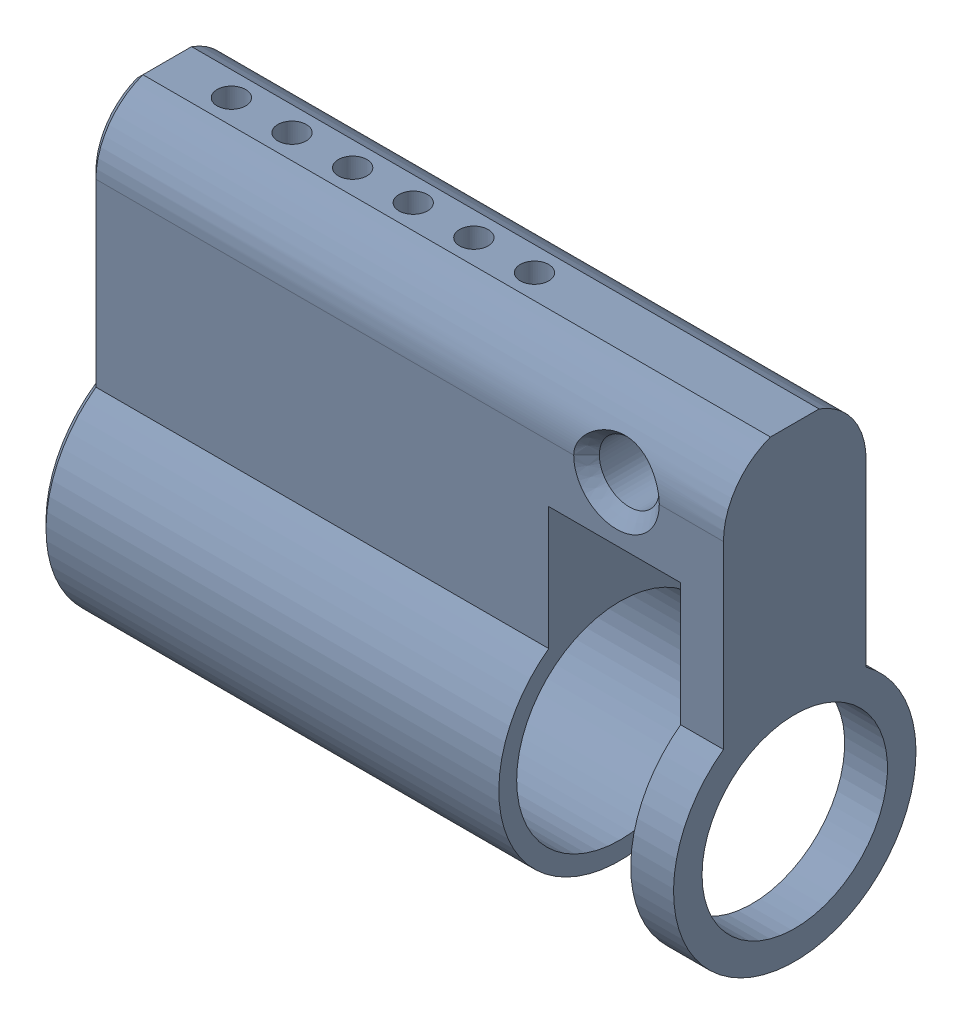
SolidWorks assembly cylinder_6-pin_sub-assembly_e, configuration Default. Lengths in mm.
Overall size (44.5 32.7 17).
6 component instances, 6 part files, 0 mates.
Components (placement in the parent):
- cylinder_d_six-pair_of_pins-1: cylinder_d_six-pair_of_pins [Default] at origin size (44.5 32.7 17)
- upper_half_pin_y_cut_depth_2-1: upper_half_pin_y_cut_depth_2 [Default] at (5 15.25 0) x (0.989024 0 0.147752) z (0 -1 0) size (2 2 8)
- upper_half_pin_y_cut_depth_4-1: upper_half_pin_y_cut_depth_4 [Default] at (9.25 13.25 0) x (0.53788 0 0.843022) z (0 -1 0) size (2 2 6)
- upper_half_pin_y_cut_depth_5-1: upper_half_pin_y_cut_depth_5 [Default] at (13.5 12.25 0) x (0.923388 0 0.383868) z (0 -1 0) size (2 2 5)
- upper_half_pin_y_cut_depth_1-1: upper_half_pin_y_cut_depth_1 [Default] at (22 16.4 0) x (-0.223246 0 0.974762) z (0 -1 0) size (2 2 9.15)
- upper_half_pin_y_cut_depth_3-1: upper_half_pin_y_cut_depth_3 [Default] at (26.25 14.25 0) x (-0.197827 0 0.980237) z (0 -1 0) size (2 2 7)
